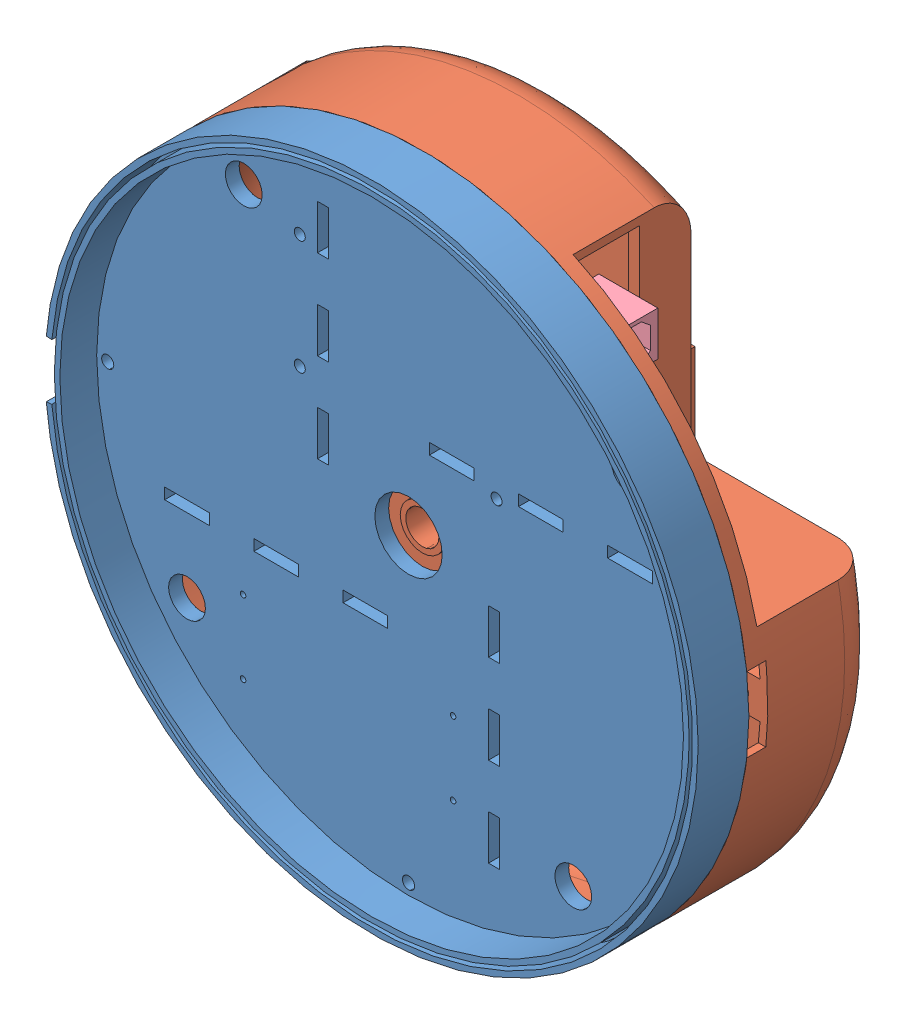
SolidWorks assembly MountAndBack, configuration Default. Lengths in mm.
Overall size (177.22 177.22 50.53).
4 component instances, 4 part files, 9 mates.
Components (placement in the parent):
- BackCover-1: BackCover [Default] at (59.4818 128.5471 115.0523) size (177.22 177.22 18.75)
- URVMount-1: URVMount [Default] at (59.4818 128.5471 111.3023) x (0 -1 0) z (0 0 1) size (177.22 177.22 36.78)
- Servo-Driver-1: Servo-Driver [Default] at (43.0849 82.2579 106.3023) x (0 0 1) z (-1 0 0) size (2 25 62.1)
- Arduino-Uno-1: Arduino-Uno [Default] at (54.6997 184.2196 96.9884) x (0 1 0) z (0 0 -1) size (54 75 15)
Mates (geometry in assembly coordinates):
- Concentric1: concentric aligned: cylinder of BackCover-1 through (59.4818 128.5471 111.3023) axis (0 0 1) radius 88.611; cylinder of URVMount-1 through (59.4818 128.5471 75.3023) axis (0 0 1) radius 88.611
- Coincident1: coincident anti-aligned: plane of BackCover-1 through (59.4818 128.5471 111.3023) normal (0 0 -1); plane of URVMount-1 through (59.4818 128.5471 111.3023) normal (0 0 1)
- Tangent1: tangent anti-aligned: face of BackHubDirect-1; plane of BackCover-1 through (83.3818 199.0471 106.3023) normal (0 0 -1)
- Tangent2: tangent anti-aligned: edge_curve of BackHubDirect-1; cylinder of BackCover-1 through (29.9818 153.5471 106.3023) axis (0 0 1) radius 1.5
- Tangent3: tangent anti-aligned: cylinder of BackCover-1 through (29.9818 184.5471 106.3023) axis (0 0 1) radius 1.5; edge_curve of Arduino-Uno-1
- Coincident2: coincident anti-aligned: plane of BackCover-1 through (59.4818 128.5471 108.3023) normal (0 0 -1); plane of ServoDriverDirect-1 through (13.5349 93.2579 108.3023) normal (0 0 1)
- Concentric2: concentric anti-aligned: cylinder of BackCover-1 through (71.5742 72.3186 108.3023) axis (0 0 1) radius 0.75; cylinder of ServoDriverDirect-1 through (71.5742 72.3186 108.3023) axis (0 0 -1) radius 1
- Concentric3: concentric anti-aligned: cylinder of BackCover-1 through (71.5742 92.1972 108.3023) axis (0 0 1) radius 0.75; cylinder of ServoDriverDirect-1 through (71.5742 92.1972 108.3023) axis (0 0 -1) radius 1
- Parallel2: parallel: plane of BackCover-1 through (59.4818 103.8471 105.0523) normal (0 1 0); line of URVMount-1 through (59.4818 128.5471 111.3023) axis (-1 0 0)
